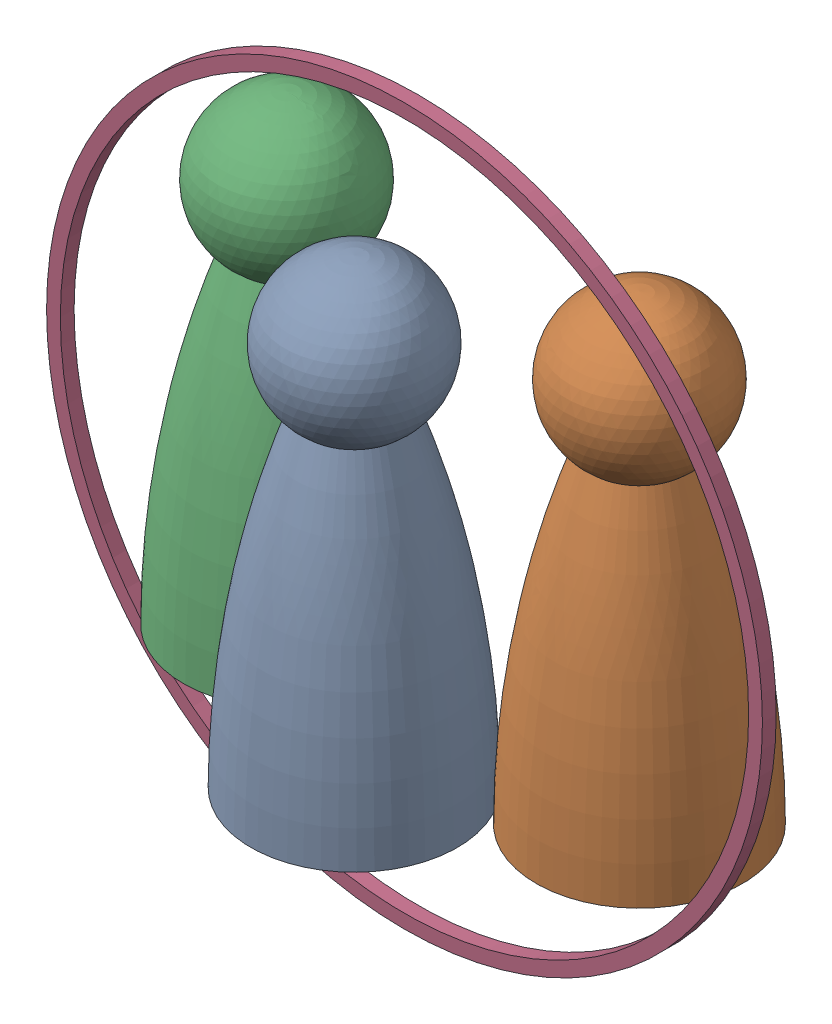
SolidWorks assembly Fuselage Profile, configuration Default. Lengths in mm.
Overall size (110.92 88.9 66.05).
4 component instances, 2 part files, 5 mates.
Components (placement in the parent):
- Passenger,Crew,EMT-1: Passenger,Crew,EMT [Default] at (0 0 -19.05) size (38.1 88.9 38.1)
- Passenger,Crew,EMT-2: Passenger,Crew,EMT [Default] at (32.0729 0 -39.6156) x (-0.829739 0 -0.558151) z (0.558151 0 -0.829739) size (38.1 88.9 38.1)
- Passenger,Crew,EMT-3: Passenger,Crew,EMT [Default] at (-32.4458 0 -39.022) x (0.048997 0 0.998799) z (-0.998799 0 0.048997) size (38.1 88.9 38.1)
- Fuselage sizing-2: Fuselage sizing [Default] at (-0.7218 41.9042 -31.6038) size (132.08 132.08 2.54) (hidden)
Mates (geometry in assembly coordinates):
- Tangent3: tangent: circle of Passenger,Crew,EMT-1
- Coincident7: coincident aligned: plane of Passenger,Crew,EMT-1 through (0 0 -19.05) normal (0 -1 0); plane of Passenger,Crew,EMT-3 through (-32.4458 0 -39.022) normal (0 -1 0)
- Coincident8: coincident aligned: plane of Passenger,Crew,EMT-1 through (0 0 -19.05) normal (0 -1 0); plane of Passenger,Crew,EMT-2 through (32.0729 0 -39.6156) normal (0 -1 0)
- Tangent5: tangent: circle of Passenger,Crew,EMT-1; circle of Passenger,Crew,EMT-2
- Tangent9: tangent: circle of Passenger,Crew,EMT-1; circle of Passenger,Crew,EMT-3
